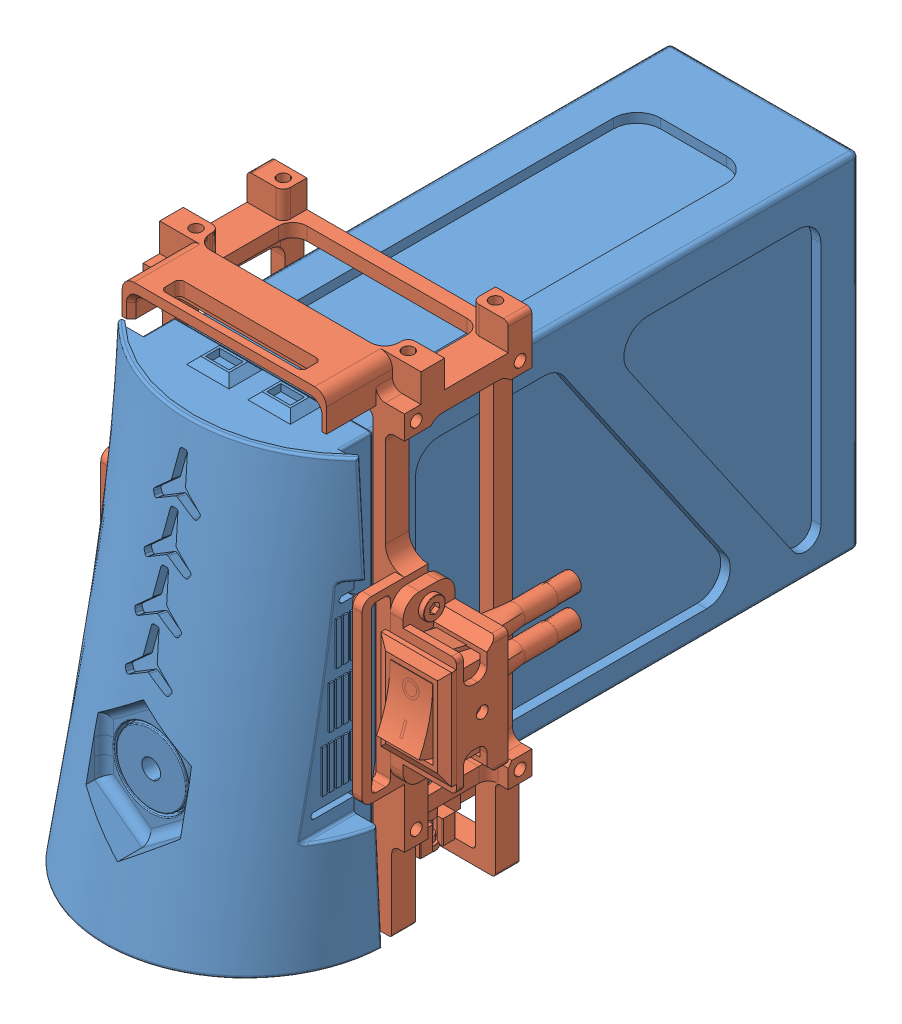
SolidWorks assembly 电池+座, configuration 默认. Lengths in mm.
Overall size (73.05 103.5 141.26).
2 component instances, 2 part files, 3 mates.
Components (placement in the parent):
- vol6.0TB47电池-1: vol6.0TB47电池 [默认] at (37.0495 -5.931 70.6306) x (0 -1 0) z (-1 0 0) size (88.55 141.26 62.7)
- 大疆电池座-2017版(1)-1: 大疆电池座-2017版(1) [开关位置-变换] at (37.0495 -7.681 147.6306) x (1 0 0) z (0 -1 0) size (69.4 39.5 103.5)
Mates (geometry in assembly coordinates):
- 重合1: coincident: plane of assembly; plane of assembly; plane of vol6.0TB47电池-1 through (59.7495 -29.131 181.6306) normal (0 0 1); plane of 大疆电池座-2017版(1)-1 through (-80.2678 -27.431 181.6306) normal (0 0 -1)
- 重合2: coincident: plane of assembly; plane of assembly; plane of vol6.0TB47电池-1 through (37.0495 -5.931 70.6306) normal (-1 0 0); plane of 大疆电池座-2017版(1)-1 through (37.0495 -7.681 147.6306) normal (1 0 0)
- 重合3: coincident: plane of assembly; plane of assembly; plane of vol6.0TB47电池-1 through (37.0495 -52.431 180.6134) normal (0 -1 0); plane of 大疆电池座-2017版(1)-1 through (-80.2678 -52.431 185.1306) normal (0 1 0)
